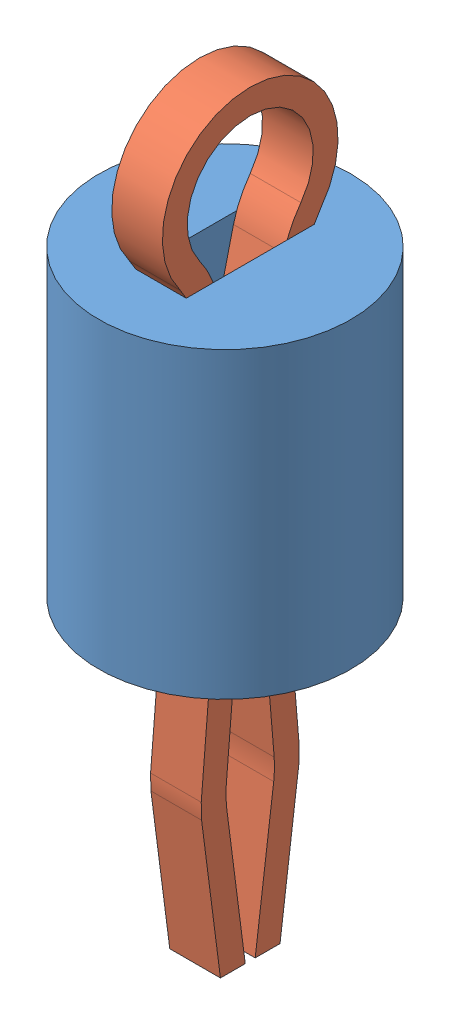
SolidWorks assembly Assem1, configuration Default. Lengths in mm.
Overall size (2.54 7.62 2.54).
2 component instances, 2 part files, 6 mates.
Components (placement in the parent):
- Spacer-orange-1: Spacer-orange [Default] x (0 0 -1) z (0 1 0) size (2.54 2.54 3.05)
- Contact-1: Contact [Default] x (0 0 -1) z (0 1 0) size (1.77 0.51 7.62)
Mates (geometry in assembly coordinates):
- Coincident1: coincident anti-aligned: plane of Spacer-orange-1 through (0 0 0) normal (-1 0 0)
- Coincident2: coincident anti-aligned: plane of Spacer-orange-1 through (0 0 0) normal (0 0 -1)
- Coincident3: coincident anti-aligned: plane of Spacer-orange-1 through (0 0 0) normal (0 -1 0)
- Coincident4: coincident anti-aligned: plane of Contact-1 through (0 0 0) normal (-1 0 0)
- Coincident5: coincident anti-aligned: plane of Contact-1 through (0 0 0) normal (0 0 -1)
- Distance1: distance = 3.05 mm aligned: plane of Spacer-orange-1 through (0 0 0) normal (0 -1 0); plane of Contact-1 through (0 -3.05 -0.175) normal (0 -1 0)
